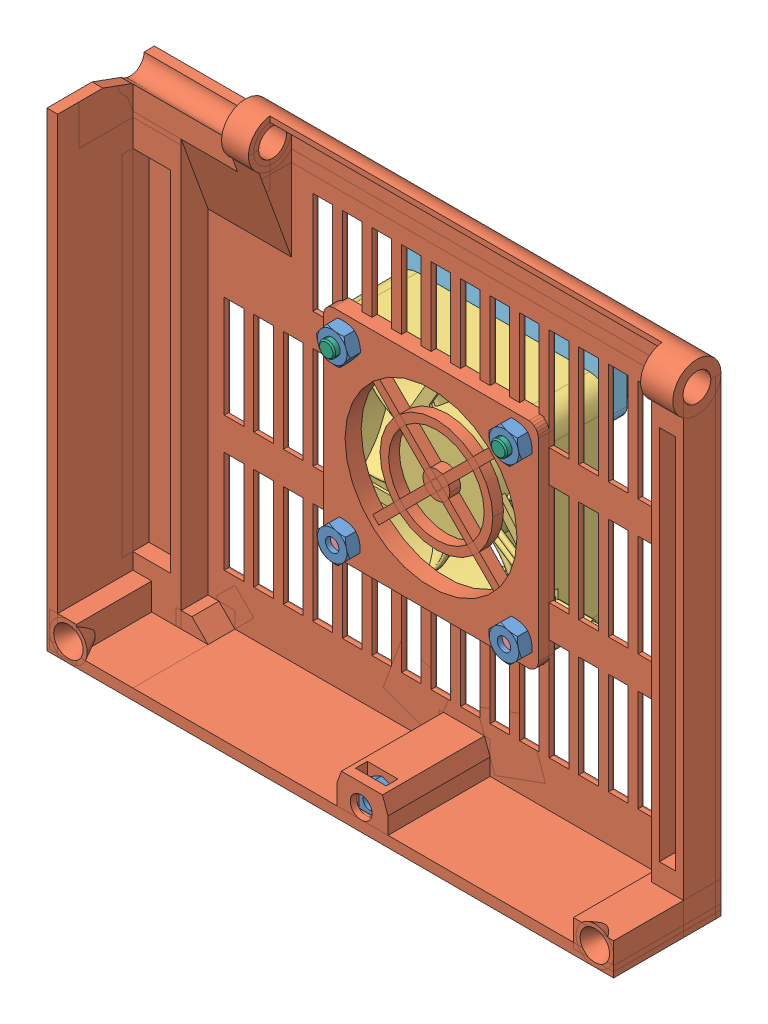
SolidWorks assembly Assembly ramps-door, configuration Valor predeterminado. Lengths in mm.
Overall size (105.5 92 36.5).
12 component instances, 6 part files, 25 mates.
Components (placement in the parent):
- Nut DIN 934 - M3-1: Nut DIN 934 - M3 [Valor predeterminado] at (60.0438 -20.5114 64.2134) x (0 0 -1) z (0 -1 0) size (2.4 5.5 6.35)
- RAMPS-cover-door-2: RAMPS-cover-door [Valor predeterminado] at (1.5438 -24.5114 47.0134) size (105.5 92 20)
- Axil flow fan - 40 x 40 x 10-2: Axil flow fan - 40 x 40 x 10 [Valor predeterminado] at (56.0438 20.4886 41.7634) size (49.86 40.69 10.5)
- Screw DIN 912 - M3 x 12 --- 12N-1: Screw DIN 912 - M3 x 12 --- 12N [Valor predeterminado] at (72.0438 4.4886 36.5134) x (0 0 -1) z (0.878851 0.477097 0) size (15 5.5 5.5)
- Screw DIN 912 - M3 x 12 --- 12N-2: Screw DIN 912 - M3 x 12 --- 12N [Valor predeterminado] at (40.0438 4.4886 36.5134) x (0 0 -1) z (0.878851 0.477097 0) size (15 5.5 5.5)
- Nut DIN 934 - M3-2: Nut DIN 934 - M3 [Valor predeterminado] at (72.0438 4.4886 51.2134) x (0 0 1) z (-0.257172 0.966366 0) size (2.4 5.5 6.35)
- Nut DIN 934 - M3-3: Nut DIN 934 - M3 [Valor predeterminado] at (40.0438 4.4886 51.2134) x (0 0 1) z (-0.257172 0.966366 0) size (2.4 5.5 6.35)
- Fan-protector-1: Fan-protector [Valor predeterminado] at (56.0438 38.1886 36.5134) x (1 0 0) z (0 0 -1) size (40 10.6 6)
- Screw DIN 912 - M3 x 20 --- 20N-1: Screw DIN 912 - M3 x 20 --- 20N [Valor predeterminado] at (72.0438 36.4886 30.5134) x (0 0 -1) z (0.437702 -0.89912 0) size (23 5.5 5.5)
- Screw DIN 912 - M3 x 20 --- 20N-2: Screw DIN 912 - M3 x 20 --- 20N [Valor predeterminado] at (40.0438 36.4886 30.5134) x (0 0 -1) z (0.437702 -0.89912 0) size (23 5.5 5.5)
- Nut DIN 934 - M3-4: Nut DIN 934 - M3 [Valor predeterminado] at (40.0438 36.4886 51.2134) x (0 0 1) z (-0.362876 0.931838 0) size (2.4 5.5 6.35)
- Nut DIN 934 - M3-5: Nut DIN 934 - M3 [Valor predeterminado] at (72.0438 36.4886 51.2134) x (0 0 1) z (-0.257172 0.966366 0) size (2.4 5.5 6.35)
Mates (geometry in assembly coordinates):
- Concêntrico1: concentric: cylinder of assembly; circle of assembly; cylinder of Nut DIN 934 - M3-1 through (60.0438 -20.5114 63.0134) axis (0 0 1) radius 1.25; circle of RAMPS-cover-door-2
- Paralelo1: parallel: plane of assembly; plane of assembly; plane of Nut DIN 934 - M3-1 through (62.7938 -18.9237 63.0134) normal (1 0 0); plane of RAMPS-cover-door-2 through (57.1938 -24.0114 63.0134) normal (1 0 0)
- Coincidente2: coincident: plane of assembly; plane of assembly; plane of Nut DIN 934 - M3-1 through (57.2938 -18.9237 63.0134) normal (0 0 -1); plane of RAMPS-cover-door-2 through (57.1938 -24.0114 63.0134) normal (0 0 1)
- Concêntrico2: concentric: cylinder of assembly; cylinder of assembly; cylinder of RAMPS-cover-door-2 through (72.0438 36.4886 47.0034) axis (0 0 1) radius 1.7; cylinder of Axil flow fan - 40 x 40 x 10-2 through (72.0438 36.4886 47.0134) axis (0 0 1) radius 1.725
- Paralelo2: parallel: plane of assembly; plane of assembly; plane of RAMPS-cover-door-2 through (107.0438 -24.5114 47.0134) normal (1 0 0); plane of Axil flow fan - 40 x 40 x 10-2 through (76.0438 36.4886 47.0134) normal (1 0 0)
- Coincidente4: coincident: plane of assembly; plane of assembly; plane of RAMPS-cover-door-2 through (56.0438 20.4886 47.0134) normal (0 0 -1); plane of Axil flow fan - 40 x 40 x 10-2 through (56.0438 20.4886 47.0134) normal (0 0 1)
- Concêntrico3: concentric: cylinder of assembly; cylinder of assembly; cylinder of Axil flow fan - 40 x 40 x 10-2 through (72.0438 4.4886 47.0134) axis (0 0 1) radius 1.725; cylinder of Screw DIN 912 - M3 x 12 --- 12N-1 through (72.0438 4.4886 36.5134) axis (0 0 -1) radius 1.5
- Coincidente6: coincident: plane of assembly; plane of assembly; plane of Axil flow fan - 40 x 40 x 10-2 through (72.0438 4.4886 39.5134) normal (0 0 -1); plane of Screw DIN 912 - M3 x 12 --- 12N-1 through (70.7317 6.9054 39.5134) normal (0 0 1)
- Coincidente7: coincident: plane of assembly; plane of assembly; plane of Axil flow fan - 40 x 40 x 10-2 through (40.0438 4.4886 39.5134) normal (0 0 -1); plane of Screw DIN 912 - M3 x 12 --- 12N-2 through (38.7317 6.9054 39.5134) normal (0 0 1)
- Concêntrico5: concentric: cylinder of assembly; cylinder of assembly; cylinder of Axil flow fan - 40 x 40 x 10-2 through (40.0438 4.4886 47.0134) axis (0 0 1) radius 1.725; cylinder of Screw DIN 912 - M3 x 12 --- 12N-2 through (40.0438 4.4886 36.5134) axis (0 0 -1) radius 1.5
- Concêntrico6: concentric: cylinder of assembly; cylinder of assembly; cylinder of Screw DIN 912 - M3 x 12 --- 12N-1 through (72.0438 4.4886 36.5134) axis (0 0 -1) radius 1.5; cylinder of Nut DIN 934 - M3-2 through (72.0438 4.4886 52.4134) axis (0 0 -1) radius 1.25
- Coincidente8: coincident: plane of assembly; plane of assembly; plane of RAMPS-cover-door-2 through (56.0438 20.4886 50.0134) normal (0 0 1); plane of Nut DIN 934 - M3-2 through (69.7946 2.247 50.0134) normal (0 0 -1)
- Concêntrico7: concentric: cylinder of assembly; cylinder of assembly; cylinder of Screw DIN 912 - M3 x 12 --- 12N-2 through (40.0438 4.4886 36.5134) axis (0 0 -1) radius 1.5; cylinder of Nut DIN 934 - M3-3 through (40.0438 4.4886 52.4134) axis (0 0 -1) radius 1.25
- Coincidente9: coincident: plane of assembly; plane of assembly; plane of RAMPS-cover-door-2 through (56.0438 20.4886 50.0134) normal (0 0 1); plane of Nut DIN 934 - M3-3 through (37.7946 2.247 50.0134) normal (0 0 -1)
- Coincidente10: coincident: plane of assembly; plane of assembly; plane of Axil flow fan - 40 x 40 x 10-2 through (40.0438 4.4886 36.5134) normal (0 0 -1); plane of Fan-protector-1 through (56.0438 38.1886 36.5134) normal (0 0 1)
- Concêntrico8: concentric: cylinder of assembly; cylinder of assembly; cylinder of Axil flow fan - 40 x 40 x 10-2 through (72.0438 36.4886 47.0134) axis (0 0 1) radius 1.725; cylinder of Fan-protector-1 through (72.0438 36.4886 3.975) axis (0 0 1) radius 1.75
- Paralelo3: parallel: plane of assembly; plane of assembly; plane of Axil flow fan - 40 x 40 x 10-2 through (40.0438 40.4886 47.0134) normal (0 1 0); plane of Fan-protector-1 through (36.0438 43.4886 33.5134) normal (0 1 0)
- Concêntrico10: concentric: cylinder of assembly; cylinder of assembly; cylinder of Fan-protector-1 through (72.0438 36.4886 3.975) axis (0 0 1) radius 1.75; cylinder of Screw DIN 912 - M3 x 20 --- 20N-1 through (72.0438 36.4886 30.5134) axis (0 0 -1) radius 1.5
- Coincidente13: coincident: plane of assembly; plane of assembly; plane of Fan-protector-1 through (56.0438 38.1886 33.5134) normal (0 0 -1); plane of Screw DIN 912 - M3 x 20 --- 20N-1 through (74.5163 37.6922 33.5134) normal (0 0 1)
- Concêntrico11: concentric: cylinder of assembly; cylinder of assembly; cylinder of Fan-protector-1 through (40.0438 36.4886 3.975) axis (0 0 1) radius 1.75; cylinder of Screw DIN 912 - M3 x 20 --- 20N-2 through (40.0438 36.4886 30.5134) axis (0 0 -1) radius 1.5
- Coincidente14: coincident: plane of assembly; plane of assembly; plane of Fan-protector-1 through (56.0438 38.1886 33.5134) normal (0 0 -1); plane of Screw DIN 912 - M3 x 20 --- 20N-2 through (42.5163 37.6922 33.5134) normal (0 0 1)
- Coincidente15: coincident: plane of assembly; plane of assembly; plane of RAMPS-cover-door-2 through (56.0438 20.4886 50.0134) normal (0 0 1); plane of Nut DIN 934 - M3-5 through (69.7946 34.247 50.0134) normal (0 0 -1)
- Concêntrico12: concentric: cylinder of assembly; cylinder of assembly; cylinder of Screw DIN 912 - M3 x 20 --- 20N-1 through (72.0438 36.4886 30.5134) axis (0 0 -1) radius 1.5; cylinder of Nut DIN 934 - M3-5 through (72.0438 36.4886 52.4134) axis (0 0 -1) radius 1.25
- Concêntrico13: concentric: cylinder of assembly; cylinder of assembly; cylinder of Screw DIN 912 - M3 x 20 --- 20N-2 through (40.0438 36.4886 30.5134) axis (0 0 -1) radius 1.5; cylinder of Nut DIN 934 - M3-4 through (40.0438 36.4886 52.4134) axis (0 0 -1) radius 1.25
- Coincidente17: coincident: plane of assembly; plane of assembly; plane of RAMPS-cover-door-2 through (56.0438 20.4886 50.0134) normal (0 0 1); plane of Nut DIN 934 - M3-4 through (38.0573 34.0112 50.0134) normal (0 0 -1)
